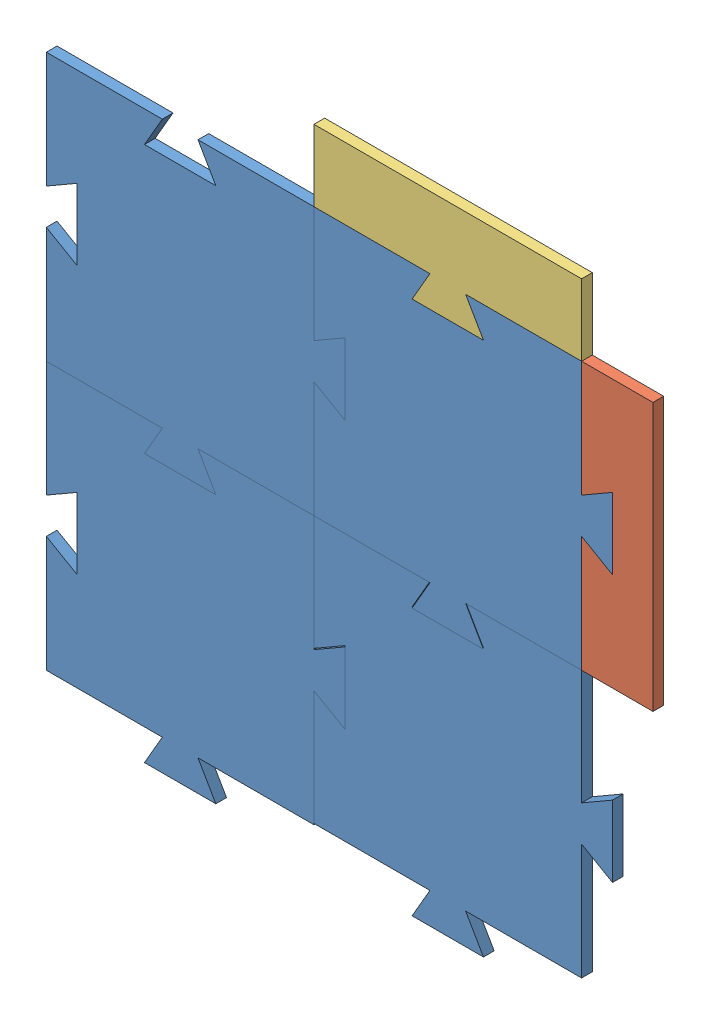
SolidWorks assembly Assemblage1, configuration Défaut. Lengths in mm.
Overall size (340 357.32 6).
6 component instances, 3 part files, 11 mates.
Components (placement in the parent):
- piece maitresse-1: piece maitresse [Défaut] at (-21.109 99.8906 164.3205) size (167.32 167.32 6)
- piece maitresse-2: piece maitresse [Défaut] at (-21.109 -50.1094 164.3205) size (167.32 167.32 6)
- piece maitresse-3: piece maitresse [Défaut] at (128.891 -49.4811 164.3205) size (167.32 167.32 6)
- piece maitresse-4: piece maitresse [Défaut] at (128.891 99.8906 164.3205) size (167.32 167.32 6)
- bord piece de puzzle 1-1: bord piece de puzzle 1 [Défaut] at (144.8208 160.7678 164.3205) x (0 -1 0) z (0 0 1) size (150 40 6)
- bord piece de puzzle 2-1: bord piece de puzzle 2 [Défaut] at (63.982 211.4009 164.3205) size (150 57.32 6)
Mates (geometry in assembly coordinates):
- Coïncidente1: coincident: plane of piece maitresse-2 through (-21.109 -50.1094 170.3205) normal (0 0 1); plane of piece maitresse-1 through (-21.109 99.8906 170.3205) normal (0 0 1)
- Coïncidente2: coincident: line of piece maitresse-1 through (1.2634 150.6027 170.3205) axis (0 1 0); line of piece maitresse-4 through (1.2634 190.6027 170.3205) axis (0 -1 0)
- Coïncidente3: coincident: line of piece maitresse-1 through (-16.0571 245.6027 170.3205) axis (-1 0 0); line of piece maitresse-4 through (48.9429 245.6027 170.3205) axis (-1 0 0)
- Coïncidente4: coincident: line of piece maitresse-1 through (-81.0571 95.6027 170.3205) axis (1 0 0); line of piece maitresse-2 through (-16.0571 95.6027 170.3205) axis (-1 0 0)
- Coïncidente5: coincident: plane of piece maitresse-1 through (-166.0571 160.6027 170.3205) normal (-1 0 0); line of piece maitresse-2 through (-166.0571 95.6027 170.3205) axis (0 -1 0)
- Coïncidente6: coincident: line of piece maitresse-2 through (-16.0571 30.6027 170.3205) axis (0 1 0); line of piece maitresse-3 through (-16.0571 96.231 170.3205) axis (0 -1 0)
- Coïncidente7: coincident: line of piece maitresse-4 through (133.9429 180.6027 170.3205) axis (0 1 0); line of bord piece de puzzle 2-1 through (133.9429 285.6027 170.3205) axis (0 -1 0)
- Coïncidente8: coincident: line of piece maitresse-4 through (133.9429 245.6027 170.3205) axis (-1 0 0); plane of bord piece de puzzle 2-1 through (63.982 211.4009 170.3205) normal (0 0 1)
- Coïncidente9: coincident: line of piece maitresse-4 through (133.9429 245.6027 170.3205) axis (-1 0 0); line of bord piece de puzzle 2-1 through (133.9429 245.6027 170.3205) axis (-1 0 0)
- Coïncidente10: coincident: line of piece maitresse-4 through (151.2634 150.6027 170.3205) axis (0 1 0); line of bord piece de puzzle 1-1 through (151.2634 190.6027 170.3205) axis (0 -1 0)
- Coïncidente11: coincident: line of bord piece de puzzle 1-1 through (173.9429 245.6027 170.3205) axis (-1 0 0); line of bord piece de puzzle 2-1 through (133.9429 245.6027 170.3205) axis (-1 0 0)
